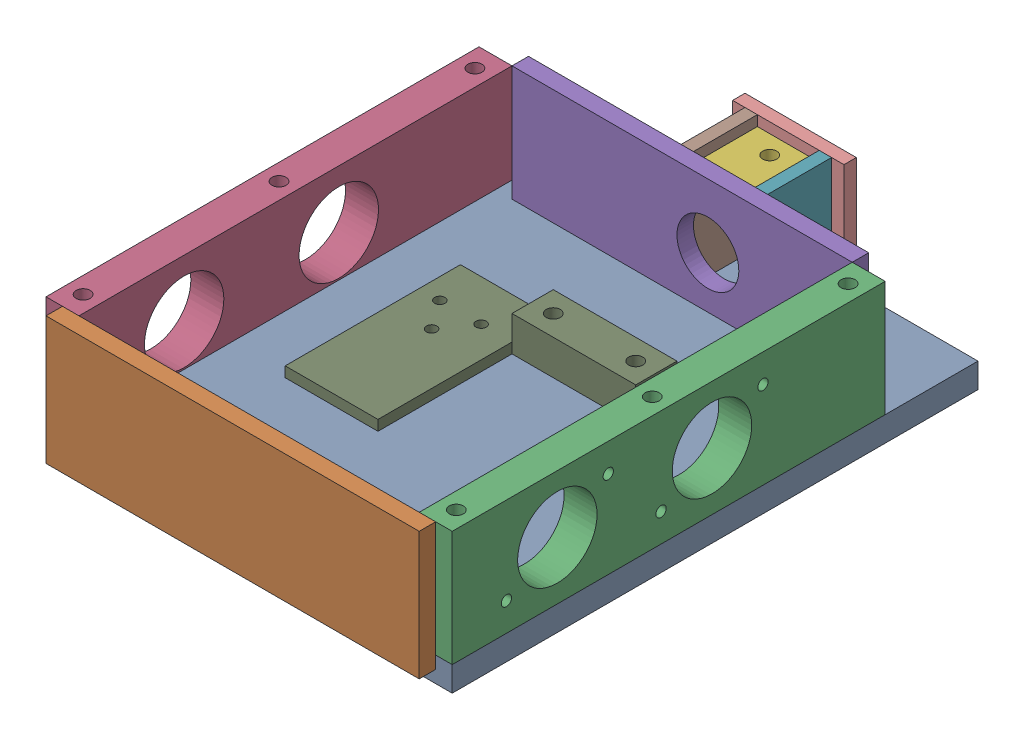
SolidWorks assembly g1_3_1_1_8_1_af0_2, configuration 默认. Lengths in mm.
Overall size (197 68 263).
11 component instances, 10 part files, 0 mates.
Components (placement in the parent):
- g1_3_1_1_8_1-3_af1_2-1: g1_3_1_1_8_1-3_af1_2 [默认] at origin size (197 12 255)
- g1_3_1_1_8_1-1_2-1: g1_3_1_1_8_1-1_2 [默认] at (0 37 127.5) x (1 0 0) z (0 -1 0) size (181 8 62)
- g1_3_1_1_8_1-2_af1_2-1: g1_3_1_1_8_1-2_af1_2 [默认] at (98.5 40 22.5) x (0 1 0) z (0 0 1) size (56 16 210)
- g1_3_1_1_8_1-2_af0_2-1: g1_3_1_1_8_1-2_af0_2 [默认] at (-98.5 40 22.5) x (0 1 0) z (0 0 -1) size (56 16 210)
- g1_3_1_1_8_1-5_2-1: g1_3_1_1_8_1-5_2 [默认] at (0 40 -82.5) x (1 0 0) z (0 1 0) size (165 8 56)
- g1_3_1_1_8_1-7_af0_2-1: g1_3_1_1_8_1-7_af0_2 [默认] at (12.5 57 -106) size (30 6 31)
- g1_3_1_1_8_1-6_2-1: g1_3_1_1_8_1-6_2 [默认] at (27.5 40 -106) x (0 1 0) z (0 0 -1) size (56 6 31)
- g1_3_1_1_8_1-6_2-2: g1_3_1_1_8_1-6_2 [默认] at (-8.5 40 -106) x (0 1 0) z (0 0 -1) size (56 6 31)
- g1_3_1_1_8_1-4_af1_2-1: g1_3_1_1_8_1-4_af1_2 [默认] at (-10 12 5) size (105 17 85)
- g1_3_1_1_8_1-8_af0_2-1: g1_3_1_1_8_1-8_af0_2 [默认] at (12.5 40 -127.5) x (0 1 0) z (1 0 0) size (56 6 54)
- g1_3_1_1_8_1_af0_more_2-1: g1_3_1_1_8_1_af0_more_2 [默认] at origin size (197 61 238)
